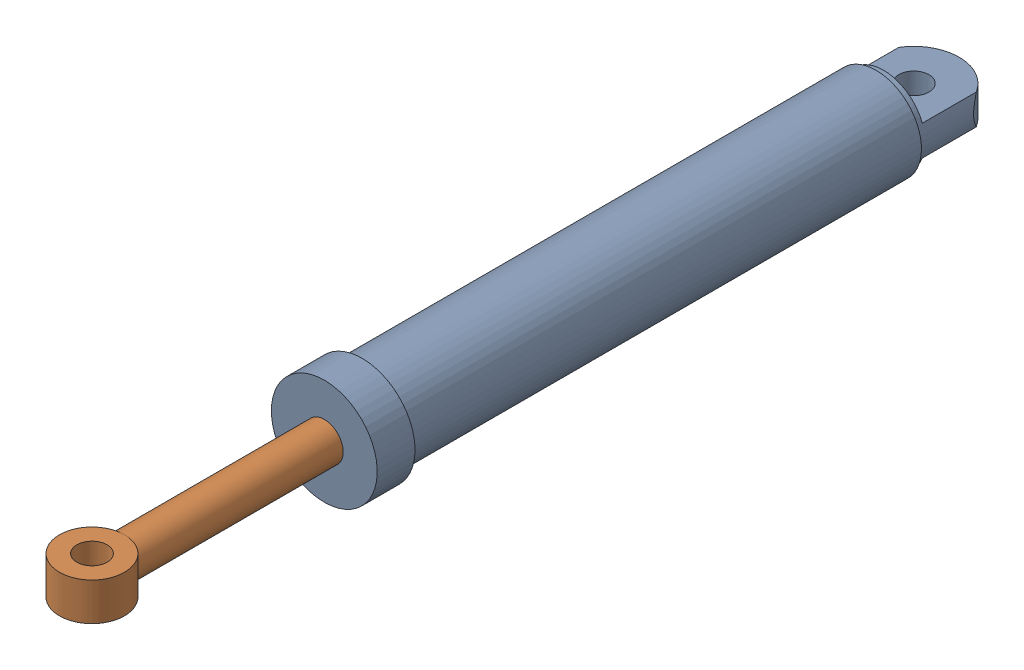
SolidWorks assembly SylinderA, configuration Default. Lengths in mm.
Overall size (140 140 1190.39).
2 component instances, 2 part files, 2 mates.
Components (placement in the parent):
- SylHusingA-1: SylHusingA [Default] at origin size (140 140 840)
- SylStempelA-1: SylStempelA [Default] at (0 0 232.3882) size (90 90 823)
Mates (geometry in assembly coordinates):
- Coincident2: coordinate: point of SylHusingA-1
- Concentric1: concentric aligned: cylinder of SylHusingA-1 through (0 0 0) axis (0 0 -1) radius 45; cylinder of SylStempelA-1 through (0 0 307.3882) axis (0 0 -1) radius 45
